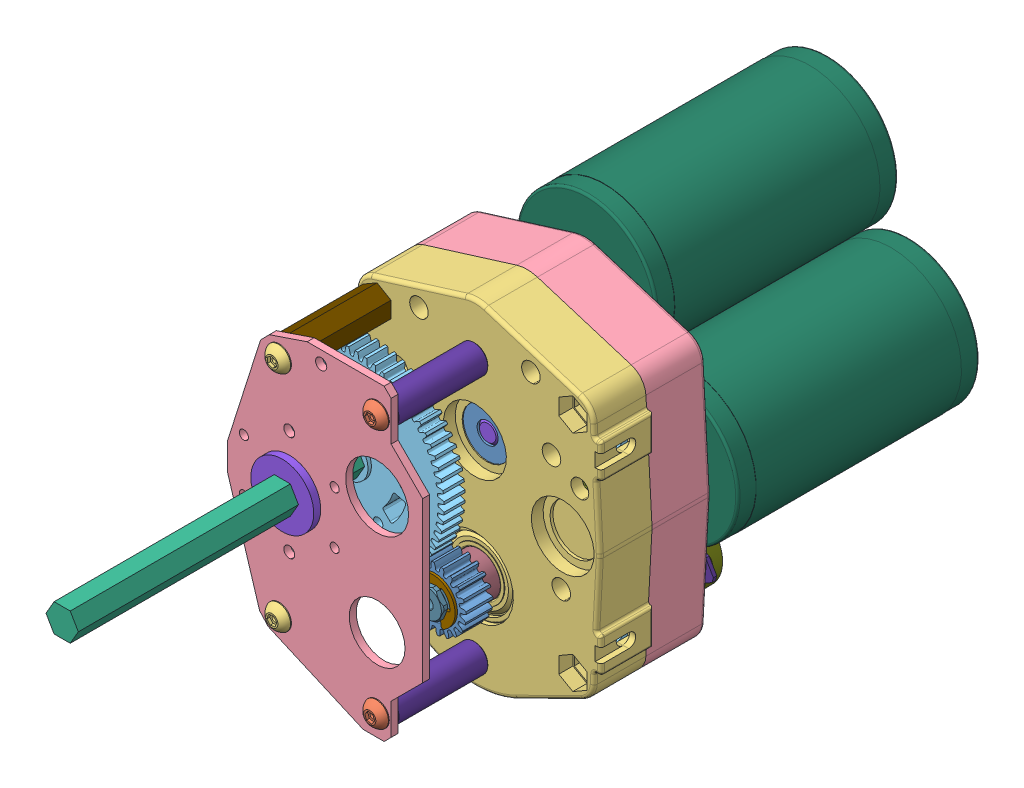
SolidWorks assembly VEXPro 3 CIM Ballshifter with WCD 3rd Stage, configuration Default. Lengths in mm.
Overall size (153.68 185.06 312.65).
102 component instances, 57 part files, 0 mates.
Components (placement in the parent):
- 217-2733-001 Rev2-1: 217-2733-001 Rev2 [Default] at (0 53.4162 37.6682) x (0 0 1) z (-0.00054 -1 0) size (7.11 24.61 24.61)
- 217-2733-001 Rev2-2: 217-2733-001 Rev2 [Default] at (0 53.4162 7.9248) x (0 0 -1) z (-0.038475 0.99926 0) size (7.11 24.61 24.61)
- 217-2731-001 Rev2-1: 217-2731-001 Rev2 [Default] at (0 0 0.0381) x (-0.099212 0.995066 0) z (0.995066 0.099212 0) size (31.12 7.94 31.12)
- 217-2789-001 Rev2-1: 217-2789-001 Rev2 [Default] at (0 0 43.2943) x (0 0 -1) z (-0.58471 0.811243 0) size (11.1 38.4 38.4)
- 217-2778-001 Rev2_NCQ8A075-050M-1: 217-2778-001 Rev2_NCQ8A075-050M [Default] at (0 0 -53.848) x (-0.707107 0.707107 0) z (0 0 1) size (31.75 33.34 52.34)
  - 217-2778-NCQ8A075-050M_NCQ8 Tube_075A-1: 217-2778-NCQ8A075-050M_NCQ8 Tube_075A [Default] at origin size (31.75 33.34 26.92)
  - 217-2778-NCQ8A075-050M_NCQ8 Rod_075M-1: 217-2778-NCQ8A075-050M_NCQ8 Rod_075M [Default] at (0 0 3.6101) x (-1 0 0) z (0 0 1) size (18.95 18.95 35.27)
  - 217-2778-NCQ8A075-050M_Snap Ring_075-1: 217-2778-NCQ8A075-050M_Snap Ring_075 [Default] at (0 0 10.362) size (21 20.74 0.97)
- 217-2428-012 Rev2-1: 217-2428-012 Rev2 [Default] at (0 0 -40.386) size (63.5 22.23 2.29)
- 217-2428-005 Rev1-1: 217-2428-005 Rev1 [Default] at (25.4 0 -19.05) x (-0.557362 -0.83027 0) z (-0.83027 0.557362 0) size (7.33 38.98 6.35)
- 217-2428-005 Rev1-2: 217-2428-005 Rev1 [Default] at (-25.4 0 -19.05) x (0.667436 0.744667 0) z (0.744667 -0.667436 0) size (7.33 38.98 6.35)
- SCREW-832-0375-1: SCREW-832-0375 [Default] at (25.4 0 -42.5958) x (0 0 1) z (-0.875404 0.483392 0) size (11.73 7.92 7.92)
- SCREW-832-0375-2: SCREW-832-0375 [Default] at (-25.4 0 -42.5958) x (0 0 1) z (-0.966319 0.257347 0) size (11.73 7.92 7.92)
- SCREW-832-0375-3: SCREW-832-0375 [Default] at (25.4 0 5.3848) x (0 0 -1) z (1 0 0) size (11.73 7.92 7.92)
- SCREW-832-0375-4: SCREW-832-0375 [Default] at (-25.4 0 5.3848) x (0 0 -1) z (0.941463 -0.337115 0) size (11.73 7.92 7.92)
- SBS1_SBS-0632-0250-1: SBS1_SBS-0632-0250 [Default] at (15.494 0 -36.2458) x (0 0 -1) z (0.854303 -0.519775 0) size (8.57 6.68 6.65)
- SBS1_SBS-0632-0250-2: SBS1_SBS-0632-0250 [Default] at (-15.494 0 -36.2458) x (0 0 -1) z (0.854303 -0.519775 0) size (8.57 6.68 6.65)
- 217-4098-100 Rev1-1: 217-4098-100 Rev1 [Default] at (0 0 -16.927) x (-0.503316 0.864103 0) z (0 0 1) size (18.03 19.79 22.46)
  - 217-4098-006 Rev2-1: 217-4098-006 Rev2 [Default] at (0 0 -4.6312) x (0 -1 0) z (0 0 -1) size (18.09 11.02 22.46)
  - 217-4098-006 Rev2-2: 217-4098-006 Rev2 [Default] at (0 0 -4.6312) x (0 1 0) z (0 0 -1) size (18.09 11.02 22.46)
  - 217-3489-001 Rev1-1: 217-3489-001 Rev1 [Default] at (0 0 -4.6312) x (0 0 1) z (-0.980217 -0.197926 0) size (4.77 12.7 12.7)
  - 97633A130_97633A130_grv-1: 97633A130_97633A130_grv [Default] at (0 0 -7.33) x (0 0 -1) z (0.979861 0.199683 0) size (0.64 8.74 7.34)
  - 91251A107_91251A107-1: 91251A107_91251A107 [Default] at (-4.8375 -6.735 -9.4343) x (0 0.863883 -0.503692) z (-1 0 0) size (4.65 4.65 10.79)
  - 91251A107_91251A107-2: 91251A107_91251A107 [Default] at (4.8375 6.735 -9.4343) x (0 0.470889 -0.882193) z (1 0 0) size (4.65 4.65 10.79)
- 217-2428-017 Rev2-1: 217-2428-017 Rev2 [Default] at (12.7 -21.997 -3.614) x (-0.578458 -0.815712 0) z (0 0 -1) size (14.73 14.73 7.37)
- 217-2428-016 Rev3_Spur01-1: 217-2428-016 Rev3_Spur01 [Default] at (0 0 -3.614) x (0.873157 -0.48744 0) z (0 0 1) size (40.67 40.74 13.32)
- 217-2428-019 Rev1-1: 217-2428-019 Rev1 [Default] at (12.7 -21.997 -20.6248) x (0.866025 0.5 0) z (0 0 1) size (50.8 19.05 1.57)
- 217-2428-006 Rev1-1: 217-2428-006 Rev1 [Default] at (32.079 -14.2875 -9.525) x (-0.752416 0.658689 0) z (0.658689 0.752416 0) size (7.33 19.93 6.35)
- 217-2428-006 Rev1-2: 217-2428-006 Rev1 [Default] at (-3.6662 -34.925 -9.525) x (0.84498 0.534798 0) z (0.534798 -0.84498 0) size (7.33 19.93 6.35)
- SCREW-832-0375-5: SCREW-832-0375 [Default] at (32.079 -14.2875 4.7498) x (0 0 -1) z (0.980613 0.195955 0) size (11.73 7.92 7.92)
- SCREW-832-0375-6: SCREW-832-0375 [Default] at (-3.6662 -34.925 5.3848) x (0 0 -1) z (-0.672515 -0.740083 0) size (11.73 7.92 7.92)
- SCREW-832-0375-7: SCREW-832-0375 [Default] at (-3.6662 -34.925 -22.8346) x (0 0 1) z (0.948865 0.315681 0) size (11.73 7.92 7.92)
- SCREW-832-0375-8: SCREW-832-0375 [Default] at (32.079 -14.2875 -22.8346) x (0 0 1) z (-0.875404 0.483392 0) size (11.73 7.92 7.92)
- 217-2614-001_12t-1: 217-2614-001_12t [Default] at (36.9798 39.6868 15.8623) x (-0.087156 0.996195 0) z (0 0 1) size (18.29 18.29 19)
- 217-2761-001 rev1-1: 217-2761-001 rev1 [Default] at (33.1943 39.3556 16.1) x (0.087156 -0.996195 0) z (0 0 1) size (2 2 20)
- 217-2761-001 rev1-2: 217-2761-001 rev1 [Default] at (-40.7653 40.018 16.1) x (0.087156 0.996195 0) z (0 0 1) size (2 2 20)
- 217-2614-001_12t-2: 217-2614-001_12t [Default] at (-36.9798 39.6868 15.8623) x (0.087156 0.996195 0) z (0 0 1) size (18.29 18.29 19)
- 217-2614-001_12t-3: 217-2614-001_12t [Default] at (0 92.8624 15.8623) x (0.97459 0.223996 0) z (0 0 1) size (18.29 18.29 19)
- 217-2761-001 rev1-3: 217-2761-001 rev1 [Default] at (-0.8512 96.5658 16.1) x (0.97459 0.223996 0) z (0 0 1) size (2 2 20)
- 217-3195-002 rev2-1: 217-3195-002 rev2 [Default] at (0 0 50.546) x (-1 0 0) z (0 0 -1) size (114.31 152.24 24.96)
- 217-3195-001 Rev1-1: 217-3195-001 Rev1 [Default] at origin size (113.41 152.24 26.86)
- Nylock Nut_NNY2520-ZC-1: Nylock Nut_NNY2520-ZC [Default] at (48.8823 73.025 37.846) x (0 0.866025 -0.5) z (-1 0 0) size (12.85 11.89 7.62)
- Nylock Nut_NNY2520-ZC-2: Nylock Nut_NNY2520-ZC [Default] at (48.8823 -3.175 37.846) x (0 0 -1) z (-1 0 0) size (12.85 11.89 7.62)
- Nylock Nut_NNY2520-ZC-3: Nylock Nut_NNY2520-ZC [Default] at (44.45 85.725 7.8613) x (0 1 0) z (0 0 -1) size (12.85 11.89 7.62)
- 276-1027-001-1: 276-1027-001 [Default] at (47.625 58.1787 6.35) x (0 1 0) z (-1 0 0) size (8.61 5.64 9.94)
- 276-1027-001-2: 276-1027-001 [Default] at (-47.625 58.1787 6.35) x (0 -1 0) z (1 0 0) size (8.61 5.64 9.94)
- SCREW-832-1750-1: SCREW-832-1750 [Default] at (-47.625 58.1787 47.0408) x (0 0 -1) z (-0.960822 -0.277167 0) size (46.66 7.92 7.92)
- SCREW-832-1750-2: SCREW-832-1750 [Default] at (47.625 58.1787 47.0408) x (0 0 -1) z (-0.960822 -0.277167 0) size (46.66 7.92 7.92)
- Nylock Nut_NNY2520-ZC-4: Nylock Nut_NNY2520-ZC [Default] at (44.45 -15.875 7.8613) x (0 1 0) z (0 0 -1) size (12.85 11.89 7.62)
- 217-2428-004 Rev3-1: 217-2428-004 Rev3 [Default] at (0 53.4162 22.7711) x (-0.709585 0.70462 0) z (0 0 1) size (11 9.53 43.92)
- SBS1_SBS-2520-1625SS-1: SBS1_SBS-2520-1625SS [Default] at (44.45 85.725 42.4688) x (0 0 -1) z (-0.251219 0.96793 0) size (45.3 11.2 11.18)
- SBS1_SBS-2520-1625SS-2: SBS1_SBS-2520-1625SS [Default] at (44.45 -15.875 42.4688) x (0 0 -1) z (-0.251219 0.96793 0) size (45.3 11.2 11.18)
- SBS1_SBS2520-1750-1: SBS1_SBS2520-1750 [Default] at (-44.45 85.725 7.4422) x (0 0 1) z (-0.031478 0.999504 0) size (48.48 11.2 11.18)
- SBS1_SBS2520-1750-2: SBS1_SBS2520-1750 [Default] at (-44.45 -15.875 7.4422) x (0 0 1) z (-0.937114 -0.349025 0) size (48.48 11.2 11.18)
- 217-2428-021 Rev1-1: 217-2428-021 Rev1 [Default] at (0 53.4162 9.5123) x (0.451333 -0.892356 0) z (0 0 1) size (15.88 15.88 3.17)
- 217-2428-029 Rev1-1: 217-2428-029 Rev1 [Default] at (0 53.4162 36.957) x (0.999846 0.017557 0) z (0 0 1) size (15.88 15.88 1.12)
- Grayhill Lock Washer-1: Grayhill Lock Washer [Default] at (12.7 -21.997 -18.6817) x (0.467173 -0.884166 0) z (0 0 1) size (19.69 19.69 0.74)
- Grayhill Nut-1: Grayhill Nut [Default] at (12.7 -21.997 -17.0434) x (0.984088 0.177684 0) z (0 0 1) size (18.33 15.88 2.54)
- 217-2000-1: 217-2000 [Default] at (0 92.8624 0) x (0 0 -1) z (0.223996 -0.97459 0) size (150.2 64.01 64.01)
- 217-2000-2: 217-2000 [Default] at (-36.9798 39.6868 0) x (0 0 -1) z (0.996195 -0.087156 0) size (150.2 64.01 64.01)
- 217-2000-3: 217-2000 [Default] at (36.9798 39.6868 0) x (0 0 -1) z (0.996195 0.087156 0) size (150.2 64.01 64.01)
- Grahill Encoder-1: Grahill Encoder [Default] at (12.7 -21.997 -16.1798) x (-0.580071 0.814566 0) z (-0.814566 -0.580071 0) size (31.75 31.12 31.75)
- 217-3195-009 Rev1_wcd 2-1: 217-3195-009 Rev1_wcd 2 [Default] at (0 85.725 50.546) x (-0.998427 -0.056065 0) z (0 0 1) size (12.7 12.7 41.27)
- 217-3195-006 Rev1_WCD-1: 217-3195-006 Rev1_WCD [Default] at (-44.45 85.725 44.1452) x (0.5 0.866025 0) z (0 0 1) size (12.7 14.66 47.62)
- 217-3195-009 Rev1_wcd 2-2: 217-3195-009 Rev1_wcd 2 [Default] at (0 -31.75 50.546) x (0.947633 0.319361 0) z (0 0 1) size (12.7 12.7 41.27)
- 217-3195-006 Rev1_WCD-2: 217-3195-006 Rev1_WCD [Default] at (-44.45 -15.875 44.1452) x (0.5 -0.866025 0) z (0 0 1) size (12.7 14.66 47.62)
- 217-2702-001_20t-1: 217-2702-001_20t [Default] at (0 0 62.357) x (0.928499 -0.371334 0) z (0 0 1) size (28.2 28.2 12.65)
- Nylock Nut_NNY2520-ZC-5: Nylock Nut_NNY2520-ZC [Default] at (0 -31.75 45.0723) x (-0.5 0.866025 0) z (0 0 -1) size (12.85 11.89 7.62)
- Nylock Nut_NNY2520-ZC-6: Nylock Nut_NNY2520-ZC [Default] at (0 85.725 45.0723) x (-0.5 0.866025 0) z (0 0 -1) size (12.85 11.89 7.62)
- SBS1_SBS-2520-2250-1: SBS1_SBS-2520-2250 [Default] at (0 -31.75 98.298) x (0 0 -1) z (-0.933488 -0.358607 0) size (61.18 11.22 11.17)
- SBS1_SBS2520-0625ZC-1: SBS1_SBS2520-0625ZC [Default] at (-44.45 85.725 98.298) x (0 0 -1) z (0.400817 0.916158 0) size (19.57 11.22 11.17)
- SBS1_SBS2520-0625ZC-2: SBS1_SBS2520-0625ZC [Default] at (-44.45 -15.875 98.298) x (0 0 -1) z (-0.75178 -0.659414 0) size (19.57 11.22 11.17)
- SBS1_SBS-2520-2250-2: SBS1_SBS-2520-2250 [Default] at (0 85.725 98.298) x (0 0 -1) z (0.056677 -0.998393 0) size (61.18 11.22 11.17)
- 217-3195-003 rev2-1: 217-3195-003 rev2 [Default] at (0 0 94.9452) size (88.62 139.7 3.17)
- 217-2715-001_64t-1: 217-2715-001_64t [Default] at (-39.878 35.5392 61.7541) x (0 -1 0) z (0 0 -1) size (84.3 84.3 12.65)
- 217-2617-003 Rev1-1: 217-2617-003 Rev1 [Default] at (-39.878 35.5392 121.8535) x (-0.5 -0.866025 0) z (0 0 1) size (14.66 12.7 152.4)
- 217-3109-001 Rev1-1: 217-3109-001 Rev1 [Default] at (-39.878 35.5392 49.1808) x (0 0 1) z (0.312889 -0.94979 0) size (7.94 28.57 28.57)
- 217-2734-001 Rev3-1: 217-2734-001 Rev3 [Default] at (-39.878 35.5392 98.1202) x (1 0 0) z (0 1 0) size (31.12 7.94 31.12)
- 217-2617-004 Rev1_97431A340_grv-1: 217-2617-004 Rev1_97431A340_grv [Default] at (-39.878 35.5392 54.8961) x (0 0 1) z (-0.124043 -0.992277 0) size (1.07 20.42 18.58)
- 217-2617-004 Rev1_97431A340_grv-2: 217-2617-004 Rev1_97431A340_grv [Default] at (0 0 69.215) x (0 0 1) z (-0.124043 -0.992277 0) size (1.07 20.42 18.58)
- 217-3288-001 Rev3-1: 217-3288-001 Rev3 [Default] at (0 0 0.0889) x (-0.371334 -0.928499 0) z (0 0 1) size (99.51 99.53 98.3)
  - 217-2428-008 Rev2-1: 217-2428-008 Rev2 [Default] at (0 0 10.2679) size (31.75 31.75 1.59)
  - 217-2428-028 Rev1_97633A250-1: 217-2428-028 Rev1_97633A250 [Default] at (0 0 37.1221) x (0 0 1) z (0.9357 -0.352797 0) size (1.07 23.39 21.18)
  - 217-4099-000 Rev2_high gear-1: 217-4099-000 Rev2_high gear [Default] x (-1 0 0) z (0 0 1) size (22.23 22.23 98.3)
    - 217-4098-005 Rev1_91612A226-1: 217-4098-005 Rev1_91612A226 [Default] at (0 0 46.2661) x (-0.144757 0 0.989467) z (0 -1 0) size (3.02 3.15 18.22)
    - 217-4098-003 Rev2-1: 217-4098-003 Rev2 [Default] x (1 0 0) z (0 0 -1) size (22.23 22.23 55.94)
    - 217-4099-002 Rev3-1: 217-4099-002 Rev3 [Default] at (0 0 53.467) x (0 0 1) z (-1 0 0) size (40.96 12.73 14.67)
    - 217-4098-004 Rev1-1: 217-4098-004 Rev1 [Default] at (0 0 14.2494) x (0.393904 0.919152 0) z (0 0 1) size (11.68 11.68 56)
  - 217-2428-007 Rev1-1: 217-2428-007 Rev1 [Default] at (7.809 4.5085 14.2494) x (-0.69071 0.455693 -0.561483) z (-0.67559 -0.683536 0.276329) size (6.35 6.35 6.35)
  - 217-2428-007 Rev1-2: 217-2428-007 Rev1 [Default] at (5.4343 3.1375 26.9494) x (-0.162331 -0.978398 0.128005) z (0.857281 -0.204076 -0.472676) size (6.35 6.35 6.35)
  - 217-3212-101 Rev1-1: 217-3212-101 Rev1 [Default] at (-11.5751 10.4131 45.3224) x (0.923728 0.383049 0) z (0 0 -1) size (46.46 46.56 12.7)
    - 217-2428-022 Rev1-1: 217-2428-022 Rev1 [Default] at (6.7035 14.0527 24.6087) size (28.57 28.57 6.1)
    - 217-3212-001 Rev1_34t-1: 217-3212-001 Rev1_34t [Default] at (6.7035 14.0527 27.9107) size (46.46 46.56 11.11)
  - 217-3222-101 Rev1-1: 217-3222-101 Rev1 [Default] at (21.0941 -5.2804 52.7371) x (-0.889163 -0.457591 0) z (0 0 -1) size (73.87 73.92 12.7)
    - 217-2428-022 Rev1-1: 217-2428-022 Rev1 [Default] at (16.3398 14.3476 19.3234) size (28.57 28.57 6.1)
    - 217-3222-001 Rev1_Spur01-1: 217-3222-001 Rev1_Spur01 [Default] at (16.3398 14.3476 22.6254) x (0.999377 0.0353 0) z (0 0 1) size (71.39 71.45 11.11)
  - 217-2428-007 Rev1-3: 217-2428-007 Rev1 [Default] at (-5.4343 3.1375 26.9494) x (0.928483 0.348617 0.128005) z (-0.251905 0.844465 -0.472676) size (6.35 6.35 6.35)
  - 217-2428-007 Rev1-4: 217-2428-007 Rev1 [Default] at (0 -6.275 26.9494) x (-0.766153 0.629782 0.128005) z (-0.605376 -0.640389 -0.472676) size (6.35 6.35 6.35)
  - 217-2428-007 Rev1-5: 217-2428-007 Rev1 [Default] at (-7.809 4.5085 14.2494) x (-0.049287 -0.826019 -0.561483) z (0.929754 -0.24331 0.276329) size (6.35 6.35 6.35)
  - 217-2428-007 Rev1-6: 217-2428-007 Rev1 [Default] at (0 -9.017 14.2494) x (0.739997 0.370326 -0.561483) z (-0.254164 0.926846 0.276329) size (6.35 6.35 6.35)
- 217-3210-001 Rev1_30t-1: 217-3210-001 Rev1_30t [Default] at (0 53.4162 30.0736) x (-0.966828 0.255427 0) z (0 0 1) size (41.01 41.12 12.65)
- 217-2711-002 Rev1_50t-1: 217-2711-002 Rev1_50t [Default] at (0 53.4162 17.4244) x (0.262208 -0.965011 0) z (0 0 1) size (66.7 66.76 12.65)
